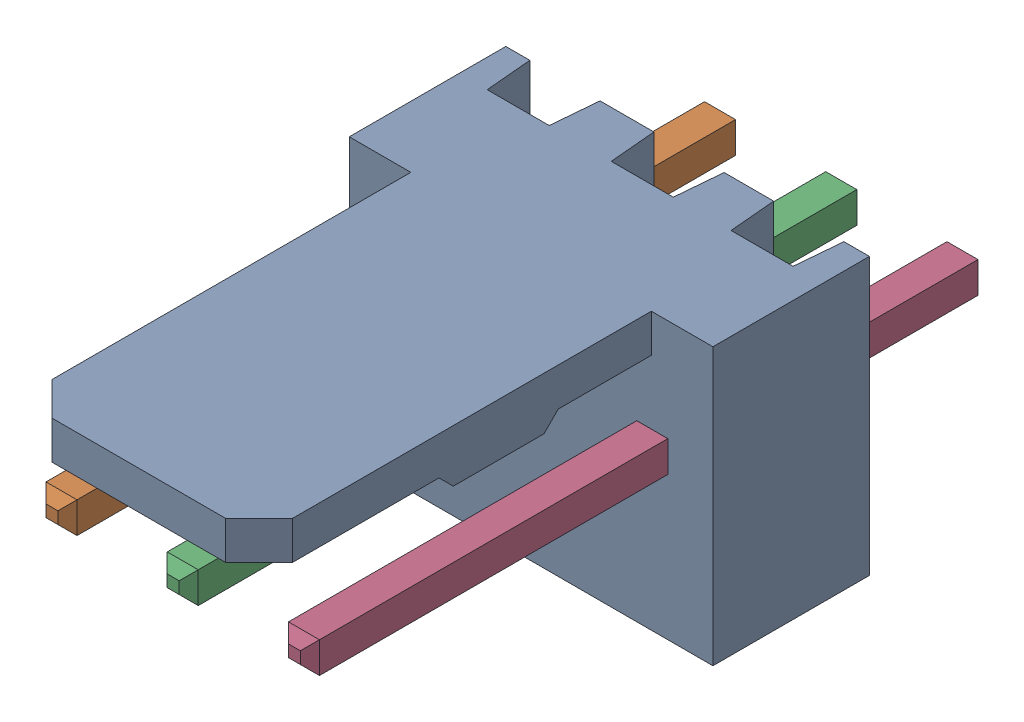
SolidWorks assembly Molex PCB 3 pin v2 v6, configuration Predeterminado. Lengths in mm.
Overall size (7.62 5.79 14.92).
4 component instances, 2 part files, 0 mates.
Components (placement in the parent):
- BASE9710016_2-1: BASE9710016_2 [Predeterminado] at (2.54 2.895 -8.22) size (7.62 5.79 11.5)
- PINO9710016_2-1: PINO9710016_2 [Predeterminado] at (1.27 3.325 -0.72) size (0.65 0.65 14.2)
- PINO9710016_2-2: PINO9710016_2 [Predeterminado] at (3.81 3.325 -0.72) size (0.65 0.65 14.2)
- PINO9710016_2-3: PINO9710016_2 [Predeterminado] at (6.35 3.325 -0.72) size (0.65 0.65 14.2)
